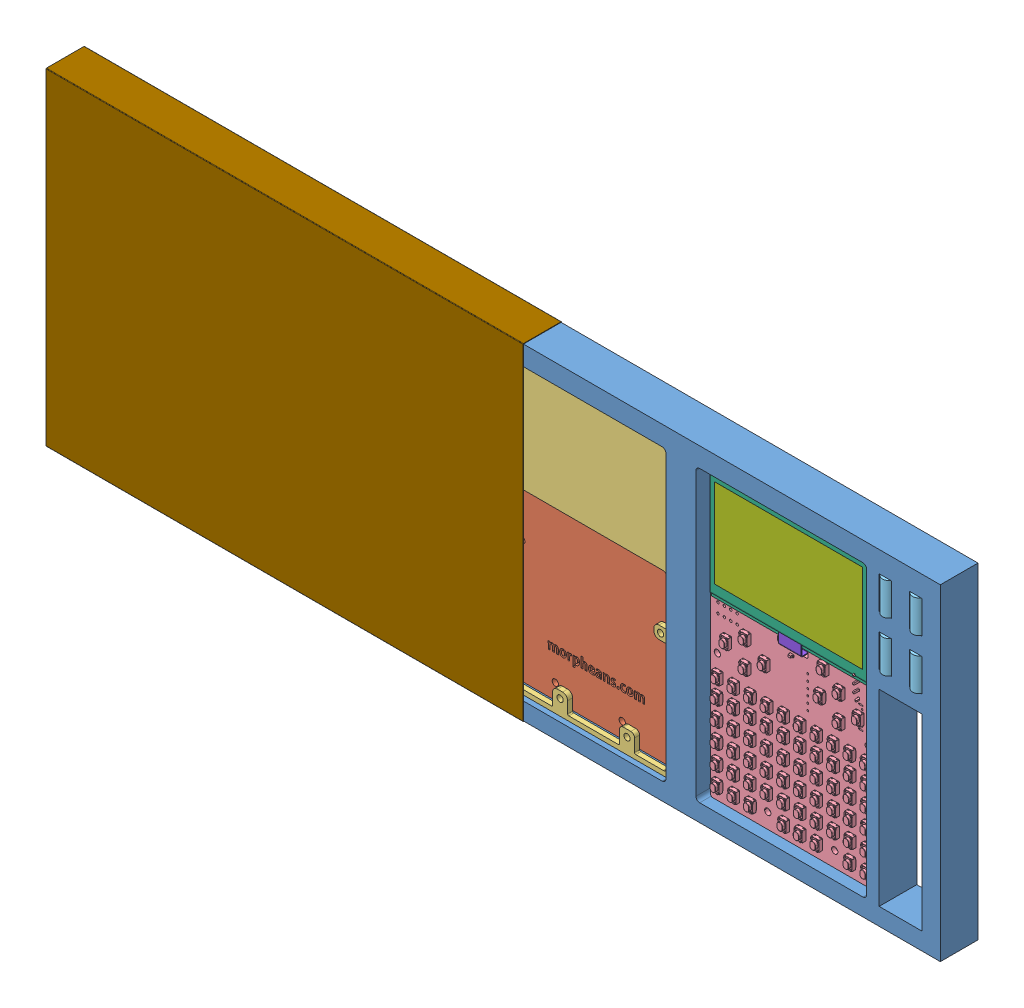
SolidWorks assembly Coque protection, configuration Défaut. Lengths in mm.
Overall size (356.04 130.4 16.32).
14 component instances, 9 part files, 10 mates.
Components (placement in the parent):
- mousse-1: mousse [Défaut] at (-237.8046 101.2015 182.5) size (190 130 15)
- cpoqueinferieure-1: cpoqueinferieure [Défaut] at (125.4149 101.2015 191) x (-1 0 0) z (0 0 -1) size (68.03 115.32 2)
- coque-dessus-1: coque-dessus [Défaut] at (-237.8046 101.1028 193.4493) size (68.03 115.32 2)
- pcbframe-1: pcbframe [Défaut] at (-157.4055 101.1028 191.5383) size (72.24 115.32 9.7)
- spacer-1: spacer [Défaut] at (77.2709 52.2583 196.1541) x (-1 0 0) z (0 -1 0) size (5 5 13)
- spacer-2: spacer [Défaut] at (77.2709 32.2583 196.1541) x (-1 0 0) z (0 -1 0) size (5 5 13)
- spacer-3: spacer [Défaut] at (65.2709 52.2583 196.1541) x (-1 0 0) z (0 -1 0) size (5 5 13)
- spacer-4: spacer [Défaut] at (65.2709 32.2583 196.1541) x (-1 0 0) z (0 -1 0) size (5 5 13)
- LS027B7DH01 LCD-1: LS027B7DH01 LCD [Défaut] at (55.3466 7.6865 193.9483) x (-1 0 0) z (0 0 -1) size (62.8 45.97 3.94)
  - LS027B7DH01 LCD.stp-1: LS027B7DH01 LCD.stp [Défaut] at origin size (62.8 45.97 3.94)
    - eBom-prt0.stp-1: eBom-prt0.stp [Défaut] at origin size (62.8 42.82 1.64)
    - eBom-prt1.stp-1: eBom-prt1.stp [Défaut] at (2 5.54 -0.835) size (58.8 35.28 0.01)
    - eBom-prt2.stp-1: eBom-prt2.stp [Défaut] at (31.4 -0.8 -0.15) x (0 -1 0) z (1 0 0) size (5.35 3.4 9)
- glissiere-1: glissiere [Défaut] at (-78.8985 -8.7106 380) x (0 0 -1) z (-1 0 0) size (15.33 130.4 190)
Mates (geometry in assembly coordinates):
- Coïncidente1: coincident anti-aligned: plane of mousse-1 through (-22.1777 101.2015 197.5) normal (-1 0 0); plane of cpoqueinferieure-1 through (-22.1777 101.2015 189) normal (1 0 0)
- Coïncidente2: coincident anti-aligned: plane of mousse-1 through (-237.8046 52.8428 197.5) normal (0 -1 0); plane of cpoqueinferieure-1 through (125.4149 52.8428 189) normal (0 1 0)
- Coïncidente3: coincident anti-aligned: plane of mousse-1 through (-237.8046 52.8428 197.5) normal (0 -1 0); plane of coque-dessus-1 through (-237.8046 52.8428 195.4493) normal (0 1 0)
- Coïncidente4: coincident anti-aligned: plane of mousse-1 through (-22.1777 101.2015 197.5) normal (-1 0 0); plane of coque-dessus-1 through (-22.1777 101.1028 195.4493) normal (1 0 0)
- Coïncidente6: coincident anti-aligned: plane of mousse-1 through (-237.8046 52.8428 197.5) normal (0 -1 0); plane of pcbframe-1 through (-7.5455 52.8428 191.5383) normal (0 1 0)
- Coïncidente7: coincident anti-aligned: plane of mousse-1 through (-237.8046 39.2583 197.5) normal (0 1 0); plane of spacer-1 through (77.2709 39.2583 196.1541) normal (0 -1 0)
- Parallèle1: parallel anti-aligned: plane of mousse-1 through (-10.212 101.2015 197.5) normal (1 0 0); plane of pcbframe-1 through (-8.8155 -13.1972 191.5383) normal (-1 0 0)
- Coïncidente10: coincident anti-aligned: plane of pcbframe-1 through (24.2045 -4.8503 193.1383) normal (0 0 1); plane of LS027B7DH01 LCD-1/LS027B7DH01 LCD.stp-1/eBom-prt0.stp-1 through (23.9466 29.0965 193.1383) normal (0 0 -1)
- Coïncidente11: coincident anti-aligned: plane of mousse-1 through (-237.8046 -69.3553 197.5) normal (0 -1 0); plane of glissiere-1 through (-268.8985 -69.3553 197.5) normal (0 1 0)
- Coïncidente12: coincident anti-aligned: plane of mousse-1 through (-237.8046 101.2015 197.5) normal (0 0 1); plane of glissiere-1 through (-268.8985 -69.3553 197.5) normal (0 0 -1)
